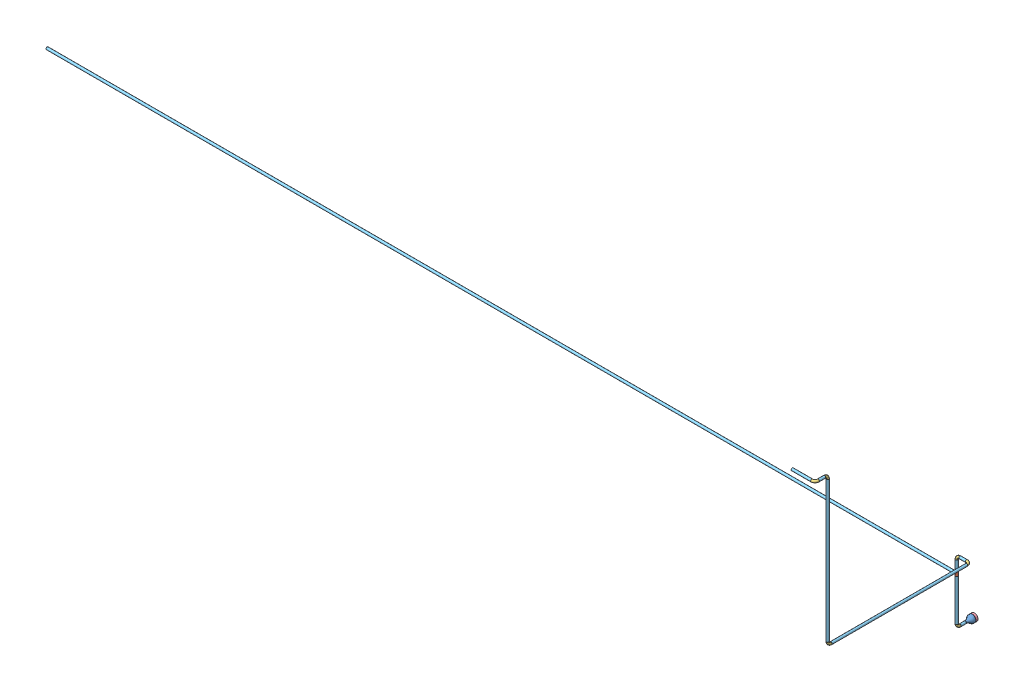
SolidWorks assembly Pipe1-SKLOP DISPOZICIJE, configuration Default. Lengths in mm.
Overall size (65430.94 15304.26 12328.9).
18 component instances, 5 part files, 0 mates.
Components (placement in the parent):
- reducer-1: reducer [REDUCER 20 x 6] at (-15235.1015 1501 -34433) x (0 0 1) z (0 1 0) size (528 508.01 508.01)
- straight tee inch-1: straight tee inch [Tee Inch 6 Sch80] at (-15235.1015 4801 -33329) x (0 1 0) z (0 0 1) size (305.5 236.89 168.28)
- 90deg LR Inch Elbow-1: 90deg LR Inch Elbow [90L LR Inch 6 Sch40] at (-15235.1015 1729.6 -33557.6) x (0 0 -1) z (-1 0 0) size (322.76 322.76 168.35)
- 90deg LR Inch Elbow-2: 90deg LR Inch Elbow [90L LR Inch 6 Sch80] at (-15006.5015 5672.4 -33329) x (0 -1 0) z (0 0 -1) size (322.75 322.75 168.35)
- 90deg LR Inch Elbow-3: 90deg LR Inch Elbow [90L LR Inch 6 Sch80] at (-14539.2015 5901 -33100.4) x (-1 0 0) z (0 -1 0) size (322.75 322.75 168.35)
- 90deg LR Inch Elbow-9: 90deg LR Inch Elbow [90L LR Inch 6 Sch80] at (-14310.6015 6129.6 -23497.6) x (0 0 -1) z (-1 0 0) size (322.75 322.75 168.35)
- 90deg LR Inch Elbow-5: 90deg LR Inch Elbow [90L LR Inch 6 Sch80] at (-14310.6015 16098.55 -23040.4) x (0 -1 0) z (1 0 0) size (322.75 322.75 168.35)
- 90deg LR Inch Elbow-6: 90deg LR Inch Elbow [90L LR Inch 6 Sch80] at (-14539.2015 16327.15 -22597.6) x (0 0 -1) z (0 -1 0) size (322.75 322.75 168.35)
- 20inSchedule60-Pipe1-SKLOP DISPOZICIJE^Pipe1-SKLOP DISPOZICIJE-1: 20inSchedule60-Pipe1-SKLOP DISPOZICIJE^Pipe1-SKLOP DISPOZICIJE [20 in, Schedule 60] at (-15235.1015 1501 -34579) x (0.707107 0.707107 0) z (0 0 1) size (508 508 146) (virtual)
- 6inSchedule40-Pipe1-SKLOP DISPOZICIJE^Pipe1-SKLOP DISPOZICIJE-1: 6inSchedule40-Pipe1-SKLOP DISPOZICIJE^Pipe1-SKLOP DISPOZICIJE [6 in, Schedule 40, 2] at (-15235.1015 1501 -33925) x (0.707107 0.707107 0) z (0 0 1) size (168.15 168.15 367.4) (virtual)
- 6inSchedule40-Pipe1-SKLOP DISPOZICIJE^Pipe1-SKLOP DISPOZICIJE-2: 6inSchedule40-Pipe1-SKLOP DISPOZICIJE^Pipe1-SKLOP DISPOZICIJE [6 in, Schedule 40, 1] at (-15235.1015 1729.6 -33329) x (0.707107 0 0.707107) z (0 1 0) size (168.15 168.15 2928.65) (virtual)
- 6inSchedule40-Pipe1-SKLOP DISPOZICIJE^Pipe1-SKLOP DISPOZICIJE-3: 6inSchedule40-Pipe1-SKLOP DISPOZICIJE^Pipe1-SKLOP DISPOZICIJE [6 in, Schedule 40, 9] at (-15235.1015 4943.748 -33329) x (0.707107 0 0.707107) z (0 1 0) size (168.15 168.15 728.65) (virtual)
- 6inSchedule40-Pipe1-SKLOP DISPOZICIJE^Pipe1-SKLOP DISPOZICIJE-4: 6inSchedule40-Pipe1-SKLOP DISPOZICIJE^Pipe1-SKLOP DISPOZICIJE [6 in, Schedule 40, 3] at (-15377.8495 4801 -33329) x (0 0.707107 0.707107) z (-1 0 0) size (168.15 168.15 64244.8) (virtual)
- 6inSchedule40-Pipe1-SKLOP DISPOZICIJE^Pipe1-SKLOP DISPOZICIJE-5: 6inSchedule40-Pipe1-SKLOP DISPOZICIJE^Pipe1-SKLOP DISPOZICIJE [6 in, Schedule 40, 4] at (-15006.5015 5901 -33329) x (0 0.707107 0.707107) z (1 0 0) size (168.15 168.15 467.3) (virtual)
- 6inSchedule40-Pipe1-SKLOP DISPOZICIJE^Pipe1-SKLOP DISPOZICIJE-6: 6inSchedule40-Pipe1-SKLOP DISPOZICIJE^Pipe1-SKLOP DISPOZICIJE [6 in, Schedule 40, 6] at (-14310.6015 5901 -33100.4) x (0.707107 0.707107 0) z (0 0 1) size (168.15 168.15 9602.8) (virtual)
- 6inSchedule40-Pipe1-SKLOP DISPOZICIJE^Pipe1-SKLOP DISPOZICIJE-7: 6inSchedule40-Pipe1-SKLOP DISPOZICIJE^Pipe1-SKLOP DISPOZICIJE [6 in, Schedule 40, 10] at (-14310.6015 6129.6 -23269) x (0.707107 0 0.707107) z (0 1 0) size (168.15 168.15 9968.95) (virtual)
- 6inSchedule40-Pipe1-SKLOP DISPOZICIJE^Pipe1-SKLOP DISPOZICIJE-8: 6inSchedule40-Pipe1-SKLOP DISPOZICIJE^Pipe1-SKLOP DISPOZICIJE [6 in, Schedule 40, 7] at (-14310.6015 16327.15 -23040.4) x (0.707107 0.707107 0) z (0 0 1) size (168.15 168.15 442.8) (virtual)
- 6inSchedule40-Pipe1-SKLOP DISPOZICIJE^Pipe1-SKLOP DISPOZICIJE-9: 6inSchedule40-Pipe1-SKLOP DISPOZICIJE^Pipe1-SKLOP DISPOZICIJE [6 in, Schedule 40, 8] at (-14539.2015 16327.15 -22369) x (0 0.707107 0.707107) z (-1 0 0) size (168.15 168.15 1371.4) (virtual)
